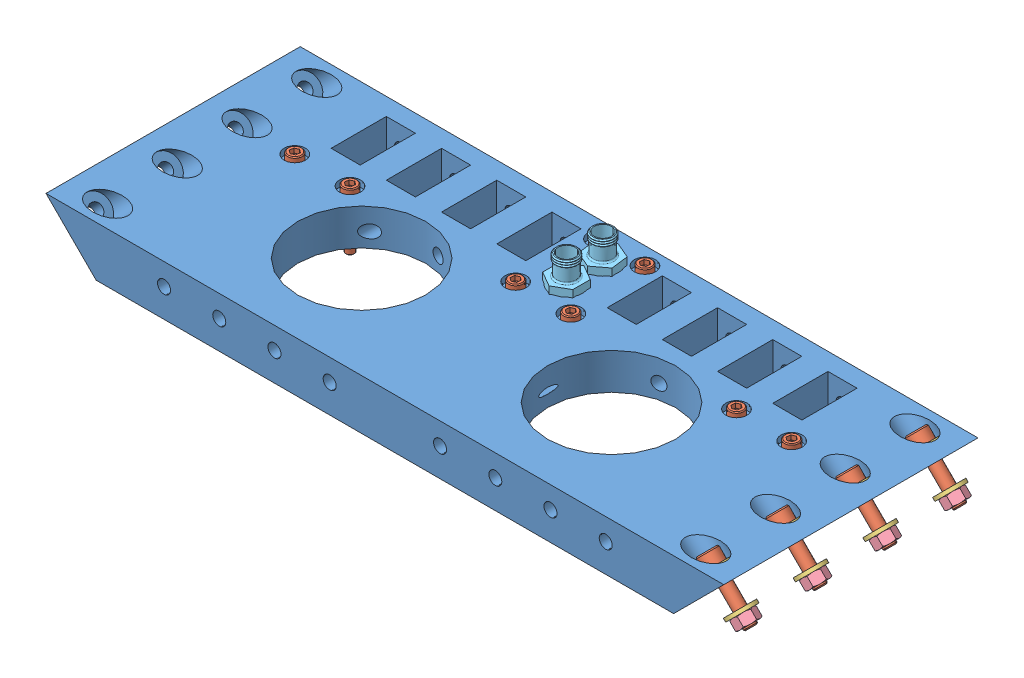
SolidWorks assembly joint_plate_assy_vert_sa_1108, configuration Default. Lengths in mm.
Overall size (476.94 58.38 175).
28 component instances, 5 part files, 9 mates.
Components (placement in the parent):
- joint_plate_vert_sa_1108-1: joint_plate_vert_sa_1108 [Default] at origin size (466.51 34.5 175)
- joint_plate_bolts_assy1x48-1: joint_plate_bolts_assy1x48 [Default] at (-0.2085 -212.2842 16) x (0.707107 -0.707107 0) z (0 0 1) size (43 18.8 162.8)
  - Socket Head Cap Screw_AM-1: Socket Head Cap Screw_AM [B18.3.1M - 8 x 1.25 x 35 Hex SHCS -- 35NHX] at (-21 313.5152 0) size (43 13 13)
  - flat washer narrow_am-1: flat washer narrow_am [B18.22M - Plain washer, 8 mm, narrow] at (-10.7 313.5152 0) size (2.3 18.8 18.8)
  - flat washer narrow_am-2: flat washer narrow_am [B18.22M - Plain washer, 8 mm, narrow] at (13.615 313.5152 0) size (2.3 18.8 18.8)
  - Hex Nut Style 1_AM-1: Hex Nut Style 1_AM [B18.2.4.1M - Hex nut, Style 1,  M8 x 1.25 --D-N] at (20.415 313.5152 0) x (0 0 -1) z (1 0 0) size (13 15.01 6.8)
  - Hex Nut Style 1_AM-2: Hex Nut Style 1_AM [B18.2.4.1M - Hex nut, Style 1,  M8 x 1.25 --D-N] at (20.415 313.5152 48) x (0 0 -1) z (1 0 0) size (13 15.01 6.8)
  - Hex Nut Style 1_AM-3: Hex Nut Style 1_AM [B18.2.4.1M - Hex nut, Style 1,  M8 x 1.25 --D-N] at (20.415 313.5152 96) x (0 0 -1) z (1 0 0) size (13 15.01 6.8)
  - Hex Nut Style 1_AM-4: Hex Nut Style 1_AM [B18.2.4.1M - Hex nut, Style 1,  M8 x 1.25 --D-N] at (20.415 313.5152 144) x (0 0 -1) z (1 0 0) size (13 15.01 6.8)
  - flat washer narrow_am-3: flat washer narrow_am [B18.22M - Plain washer, 8 mm, narrow] at (13.615 313.5152 48) size (2.3 18.8 18.8)
  - flat washer narrow_am-4: flat washer narrow_am [B18.22M - Plain washer, 8 mm, narrow] at (13.615 313.5152 96) size (2.3 18.8 18.8)
  - flat washer narrow_am-5: flat washer narrow_am [B18.22M - Plain washer, 8 mm, narrow] at (13.615 313.5152 144) size (2.3 18.8 18.8)
  - flat washer narrow_am-6: flat washer narrow_am [B18.22M - Plain washer, 8 mm, narrow] at (-10.7 313.5152 48) size (2.3 18.8 18.8)
  - flat washer narrow_am-7: flat washer narrow_am [B18.22M - Plain washer, 8 mm, narrow] at (-10.7 313.5152 96) size (2.3 18.8 18.8)
  - flat washer narrow_am-8: flat washer narrow_am [B18.22M - Plain washer, 8 mm, narrow] at (-10.7 313.5152 144) size (2.3 18.8 18.8)
  - Socket Head Cap Screw_AM-2: Socket Head Cap Screw_AM [B18.3.1M - 8 x 1.25 x 35 Hex SHCS -- 35NHX] at (-21 313.5152 48) size (43 13 13)
  - Socket Head Cap Screw_AM-3: Socket Head Cap Screw_AM [B18.3.1M - 8 x 1.25 x 35 Hex SHCS -- 35NHX] at (-21 313.5152 96) size (43 13 13)
  - Socket Head Cap Screw_AM-4: Socket Head Cap Screw_AM [B18.3.1M - 8 x 1.25 x 35 Hex SHCS -- 35NHX] at (-21 313.5152 144) size (43 13 13)
- water_adapter_b_1106-1: water_adapter_b_1106 [Default] at (0 0 50) x (0.868126 0 -0.496343) z (0 1 0) size (24 24 44)
- water_adapter_b_1106-2: water_adapter_b_1106 [Default] at (0 0 25) x (0.798683 0 -0.601752) z (0 1 0) size (24 24 44)
- Socket Head Cap Screw_AM-1: Socket Head Cap Screw_AM [B18.3.1M - 6 x 1.0 x 35 Hex SHCS -- 24NHX] at (19 26.62 66) x (0 -1 0) z (0.993148 0 0.11686) size (41 10 10)
- Socket Head Cap Screw_AM-2: Socket Head Cap Screw_AM [B18.3.1M - 6 x 1.0 x 35 Hex SHCS -- 24NHX] at (16 26.62 12) x (0 -1 0) z (0.993148 0 0.11686) size (41 10 10)
- Socket Head Cap Screw_AM-3: Socket Head Cap Screw_AM [B18.3.1M - 6 x 1.0 x 35 Hex SHCS -- 24NHX] at (-16 26.62 12) x (0 -1 0) z (0.993148 0 0.11686) size (41 10 10)
- Socket Head Cap Screw_AM-4: Socket Head Cap Screw_AM [B18.3.1M - 6 x 1.0 x 35 Hex SHCS -- 24NHX] at (-133 26.62 66) x (0 -1 0) z (0.993148 0 0.11686) size (41 10 10)
- Socket Head Cap Screw_AM-5: Socket Head Cap Screw_AM [B18.3.1M - 6 x 1.0 x 35 Hex SHCS -- 24NHX] at (133 26.62 66) x (0 -1 0) z (0.993148 0 0.11686) size (41 10 10)
- Socket Head Cap Screw_AM-6: Socket Head Cap Screw_AM [B18.3.1M - 6 x 1.0 x 35 Hex SHCS -- 24NHX] at (-171 26.62 66) x (0 -1 0) z (0.993148 0 0.11686) size (41 10 10)
- Socket Head Cap Screw_AM-7: Socket Head Cap Screw_AM [B18.3.1M - 6 x 1.0 x 35 Hex SHCS -- 24NHX] at (171 26.62 66) x (0 -1 0) z (0.993148 0 0.11686) size (41 10 10)
- Socket Head Cap Screw_AM-8: Socket Head Cap Screw_AM [B18.3.1M - 6 x 1.0 x 35 Hex SHCS -- 24NHX] at (-19 26.62 66) x (0 -1 0) z (0.993148 0 0.11686) size (41 10 10)
Mates (geometry in assembly coordinates):
- Coincident1: coincident aligned: plane of joint_plate_vert_sa_1108-1 through (-208.2574 0 175) normal (0 -1 0); plane of water_adapter_b_1106-2 through (0 0 25) normal (0 -1 0)
- Coincident2: coincident aligned: plane of joint_plate_vert_sa_1108-1 through (-208.2574 0 175) normal (0 -1 0); plane of water_adapter_b_1106-1 through (0 0 50) normal (0 -1 0)
- Concentric1: concentric anti-aligned: cylinder of joint_plate_vert_sa_1108-1 through (0 25 50) axis (0 1 0) radius 11; cylinder of water_adapter_b_1106-1 through (0 30 50) axis (0 -1 0) radius 12
- Concentric2: concentric anti-aligned: cylinder of joint_plate_vert_sa_1108-1 through (0 25 25) axis (0 1 0) radius 11; cylinder of water_adapter_b_1106-2 through (0 30 25) axis (0 -1 0) radius 12
- Coincident3: coincident anti-aligned: plane of joint_plate_vert_sa_1108-1 through (213.9142 16.9706 160) normal (-0.707107 0.707107 0); plane of joint_plate_bolts_assy1x48-1/flat washer narrow_am-8 through (217.1386 20.195 160) normal (0.707107 -0.707107 0)
- Concentric3: concentric anti-aligned: cylinder of joint_plate_vert_sa_1108-1 through (-13.6863 244.5711 160) axis (0.707107 -0.707107 0) radius 4.5; cylinder of joint_plate_bolts_assy1x48-1/Socket Head Cap Screw_AM-4 through (184.1804 46.7044 160) axis (-0.707107 0.707107 0) radius 4
- Concentric4: concentric anti-aligned: cylinder of joint_plate_vert_sa_1108-1 through (-13.6863 244.5711 16) axis (0.707107 -0.707107 0) radius 4.5; cylinder of joint_plate_bolts_assy1x48-1/Socket Head Cap Screw_AM-1 through (184.1804 46.7044 16) axis (-0.707107 0.707107 0) radius 4
- Coincident4: coincident anti-aligned: plane of joint_plate_vert_sa_1108-1 through (22.3 20.62 66) normal (0 1 0); plane of Socket Head Cap Screw_AM-1 through (19.5843 20.62 61.0343) normal (0 -1 0)
- Concentric5: concentric aligned: cylinder of joint_plate_vert_sa_1108-1 through (19 25 66) axis (0 1 0) radius 3.3; cylinder of Socket Head Cap Screw_AM-1 through (19 58.37 66) axis (0 1 0) radius 3
